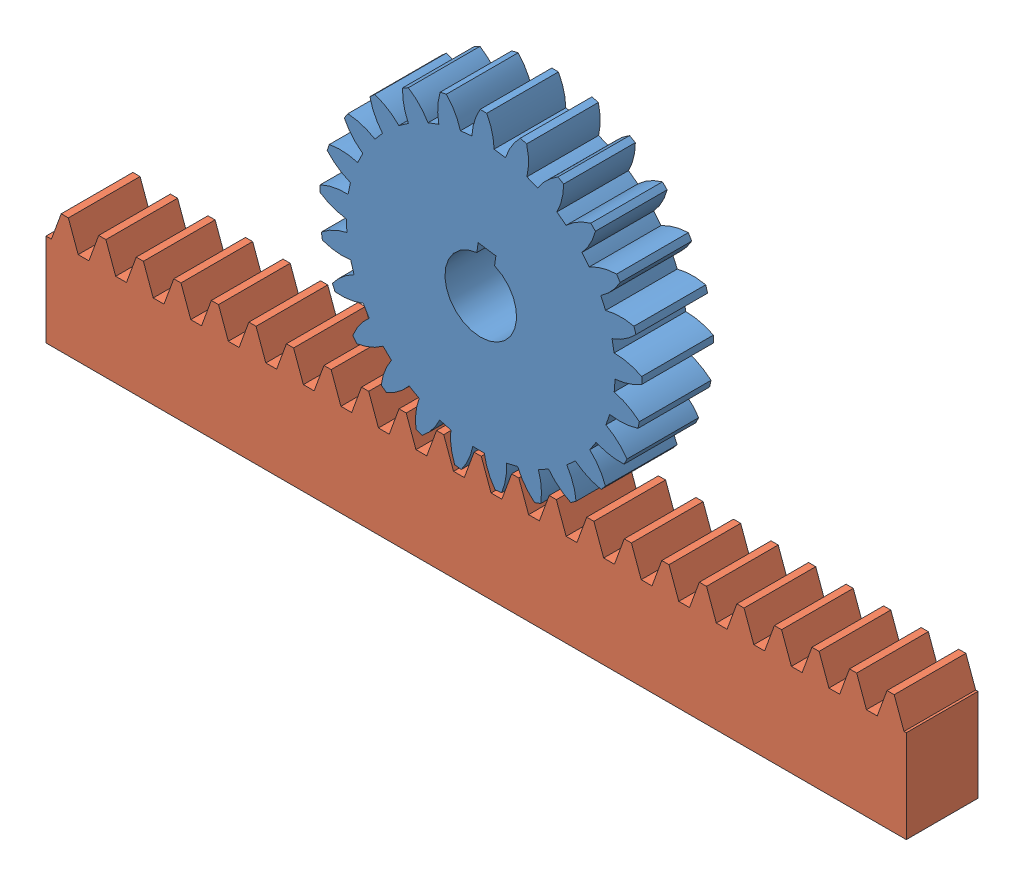
SolidWorks assembly STP10, configuration Default. Lengths in mm.
Overall size (304.8 155.79 25.4).
2 component instances, 2 part files, 6 mates.
Components (placement in the parent):
- spur gear_ai-4: spur gear_ai [Inch - Spur gear 6DP 25T 20PA 1FW ---S25N3.0H2.0L1.0S1] x (0 0 1) z (-0.989908 0.141715 0) size (25.4 113.98 114.2)
- rack spur rectangular_ai-2: rack spur rectangular_ai [Inch - Rack-spur - rectangular 6DP 20PA 1FW 1.5PH 12L---SAll] at (-154.037 -91.44 25.4) size (304.8 42.33 25.4)
Mates (geometry in assembly coordinates):
- Coincident19: coincident: plane of spur gear_ai-4 through (0 0 0) normal (0 0 -1); plane of assembly through (0 0 0) normal (0 0 1)
- Concentric7: concentric: circle of spur gear_ai-4; circle of assembly
- Coincident20: coincident: plane of spur gear_ai-4 through (0 0 0) normal (0 0 -1); plane of rack spur rectangular_ai-2 through (-154.037 -49.1067 0) normal (0 0 -1)
- Coincident21: coincident: line of rack spur rectangular_ai-2 through (304.8 -154.037 -91.44) axis (0 1 0); line of assembly
- RackPinionMate4: rack pinion = 254 mm: line of rack spur rectangular_ai-2 through (304.8 -154.037 -91.44) axis (0 1 0); circle of spur gear_ai-4
- Lock1: lock: unknown of spur gear_ai-4; unknown of rack spur rectangular_ai-2
